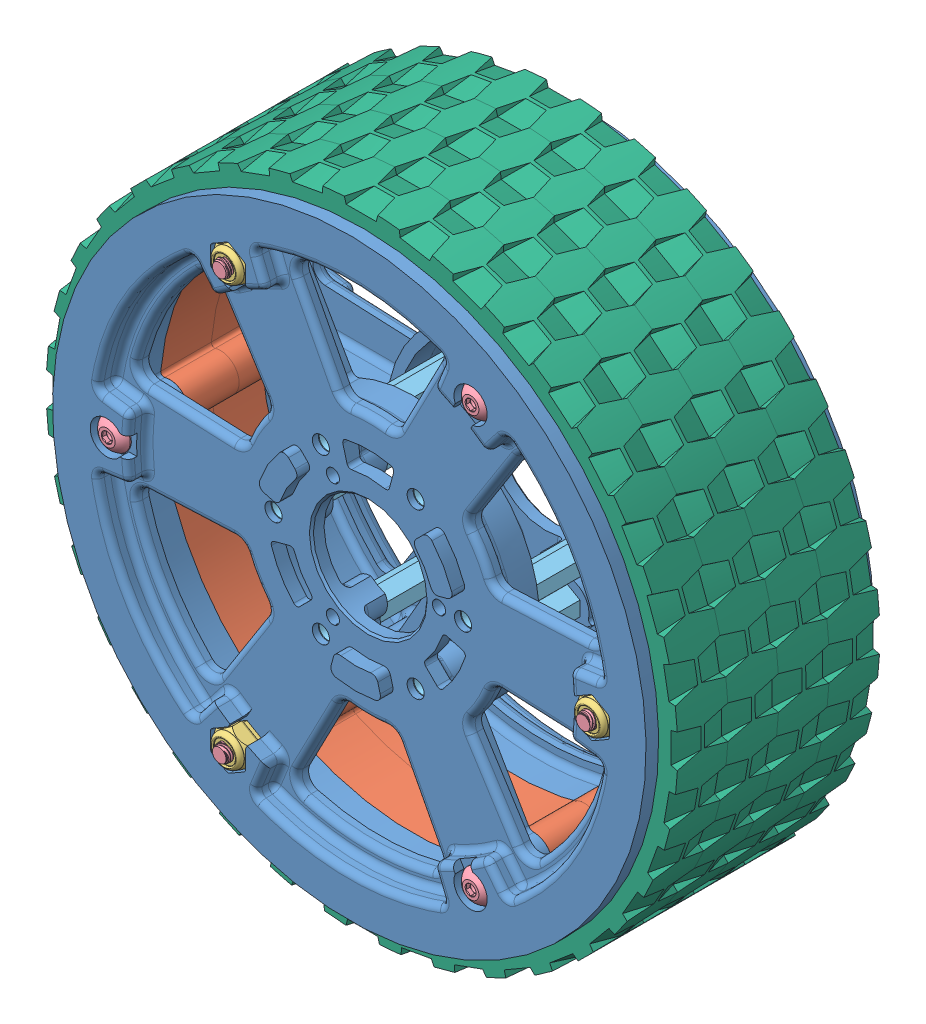
SolidWorks assembly 217-2860-on-wheel-STEP, configuration Default. Lengths in mm.
Overall size (203.85 203.85 61.62).
34 component instances, 7 part files, 0 mates.
Components (placement in the parent):
- 217-2589-001 Rev3-1: 217-2589-001 Rev3 [Default] at (-6.6039 5.1658 6.3657) size (149.22 149.22 19.81)
- 217-2589-003 Rev1-1: 217-2589-003 Rev1 [Default] at (-6.6039 5.1658 12.7157) x (0 0 -1) z (0.173648 0.984808 0) size (20.32 144.53 143.68)
- 217-2589-001 Rev3-2: 217-2589-001 Rev3 [Default] at (-6.6039 5.1658 31.7657) x (0.5 -0.866025 0) z (0 0 -1) size (149.22 149.22 19.81)
- NUT-832-NYLOCK-1: NUT-832-NYLOCK [Default] at (-67.5639 5.1658 -5.7031) x (0.866025 -0.5 0) z (0.5 0.866025 0) size (10.2 5.86 8.12)
- 832-2250_91255A206-1: 832-2250_91255A206 [Default] at (-67.5639 5.1658 45.4182) x (0.994604 -0.103745 0) z (0 0 1) size (7.98 8.02 59.89)
- 217-2589-003 Rev1-2: 217-2589-003 Rev1 [Default] at (-6.6039 5.1658 25.4157) x (0 0 -1) z (0.173648 0.984808 0) size (20.32 144.53 143.68)
- 832-2250_91255A206-2: 832-2250_91255A206 [Default] at (-37.0839 -47.6271 -7.2868) x (0.359425 0.933174 0) z (0 0 -1) size (7.98 8.02 59.89)
- NUT-832-NYLOCK-2: NUT-832-NYLOCK [Default] at (-37.0839 -47.6271 43.8346) x (0 -1 0) z (-1 0 0) size (10.2 5.86 8.12)
- NUT-832-NYLOCK-3: NUT-832-NYLOCK [Default] at (-37.0839 57.9587 43.8346) x (-0.866025 0.5 0) z (0.5 0.866025 0) size (10.2 5.86 8.12)
- NUT-832-NYLOCK-4: NUT-832-NYLOCK [Default] at (54.3561 5.1658 43.8346) x (0.866025 0.5 0) z (0.5 -0.866025 0) size (10.2 5.86 8.12)
- NUT-832-NYLOCK-5: NUT-832-NYLOCK [Default] at (23.8761 57.9587 -5.7031) x (-0.866025 -0.5 0) z (0.5 -0.866025 0) size (10.2 5.86 8.12)
- NUT-832-NYLOCK-6: NUT-832-NYLOCK [Default] at (23.8761 -47.6271 -5.7031) x (0 1 0) z (-1 0 0) size (10.2 5.86 8.12)
- 832-2250_91255A206-3: 832-2250_91255A206 [Default] at (23.8761 57.9587 45.4182) x (-0.587147 -0.80948 0) z (0 0 1) size (7.98 8.02 59.89)
- 832-2250_91255A206-4: 832-2250_91255A206 [Default] at (23.8761 -47.6271 45.4182) x (-0.407457 0.913225 0) z (0 0 1) size (7.98 8.02 59.89)
- 832-2250_91255A206-5: 832-2250_91255A206 [Default] at (-37.0839 57.9587 -7.2868) x (0.62844 -0.777858 0) z (0 0 -1) size (7.98 8.02 59.89)
- 832-2250_91255A206-6: 832-2250_91255A206 [Default] at (54.3561 5.1658 -7.2868) x (-0.987865 -0.155316 0) z (0 0 -1) size (7.98 8.02 59.89)
- 217-2588-005 Rev1-1: 217-2588-005 Rev1 [Default] at (-18.5101 25.788 19.1292) x (0 1 0) z (1 0 0) size (7.34 45.33 7.34)
- 217-2588-005 Rev1-2: 217-2588-005 Rev1 [Default] at (5.3024 25.788 19.1292) x (0.866025 0.5 0) z (0.5 -0.866025 0) size (7.34 45.33 7.34)
- 217-2588-005 Rev1-3: 217-2588-005 Rev1 [Default] at (17.2086 5.1658 19.1292) x (0.866025 -0.5 0) z (-0.5 -0.866025 0) size (7.34 45.33 7.34)
- 217-2588-005 Rev1-4: 217-2588-005 Rev1 [Default] at (5.3024 -15.4564 19.1292) x (0 -1 0) z (-1 0 0) size (7.34 45.33 7.34)
- 217-2588-005 Rev1-5: 217-2588-005 Rev1 [Default] at (-18.5101 -15.4564 19.1292) x (-0.866025 -0.5 0) z (-0.5 0.866025 0) size (7.34 45.33 7.34)
- 217-2588-005 Rev1-6: 217-2588-005 Rev1 [Default] at (-30.4164 5.1658 19.1292) x (-0.866025 0.5 0) z (0.5 0.866025 0) size (7.34 45.33 7.34)
- 217-2860-000 Rev2-1: 217-2860-000 Rev2 [Default] at (-6.6039 5.1658 0.0157) x (0.999997 0.002561 0) z (0 0 1) size (158.75 158.75 12.71)
  - 217-2860-001 Rev3-1: 217-2860-001 Rev3 [Default] at origin size (158.75 158.75 12.71)
  - 217-2860-011 Rev1-1: 217-2860-011 Rev1 [Default] at origin size (146.53 146.53 8.05)
- 217-2860-000 Rev2-2: 217-2860-000 Rev2 [Default] at (-6.6039 5.1658 12.7157) x (0.999997 0.002561 0) z (0 0 1) size (158.75 158.75 12.71)
  - 217-2860-001 Rev3-1: 217-2860-001 Rev3 [Default] at origin size (158.75 158.75 12.71)
  - 217-2860-011 Rev1-1: 217-2860-011 Rev1 [Default] at origin size (146.53 146.53 8.05)
- 217-2860-000 Rev2-3: 217-2860-000 Rev2 [Default] at (-6.6039 5.1658 25.4157) x (0.999997 0.002561 0) z (0 0 1) size (158.75 158.75 12.71)
  - 217-2860-001 Rev3-1: 217-2860-001 Rev3 [Default] at origin size (158.75 158.75 12.71)
  - 217-2860-011 Rev1-1: 217-2860-011 Rev1 [Default] at origin size (146.53 146.53 8.05)
- 217-2860-000 Rev2-4: 217-2860-000 Rev2 [Default] at (-6.6039 5.1658 38.1157) x (0.999997 0.002561 0) z (0 0 1) size (158.75 158.75 12.71)
  - 217-2860-001 Rev3-1: 217-2860-001 Rev3 [Default] at origin size (158.75 158.75 12.71)
  - 217-2860-011 Rev1-1: 217-2860-011 Rev1 [Default] at origin size (146.53 146.53 8.05)
